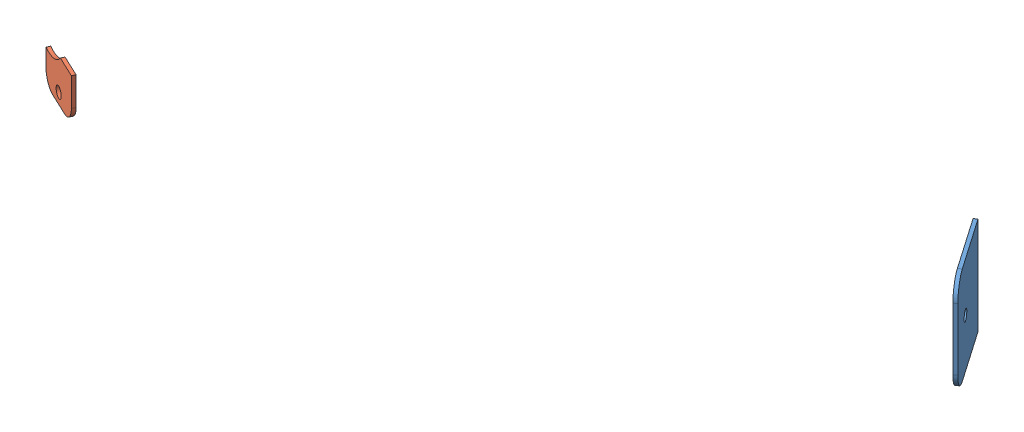
SolidWorks assembly PUTM-F-FR-MT-Chain_cover_mounting, configuration Domyślna. Lengths in mm.
Overall size (354.59 79 209.73).
2 component instances, 2 part files, 0 mates.
Components (placement in the parent):
- PUTM-F-FR-MT-Front-1: PUTM-F-FR-MT-Front [Domyślna] at (-1058.5579 102.45 732.9475) x (0 -1 0) z (0.822156 0 -0.569262) size (55 45 2)
- PUTM-F-FR-MT-Rear-1: PUTM-F-FR-MT-Rear [Domyślna] at (-452.0433 102.45 956.2533) x (-0.904074 0 -0.427377) z (-0.427377 0 0.904074) size (30 24 2)
